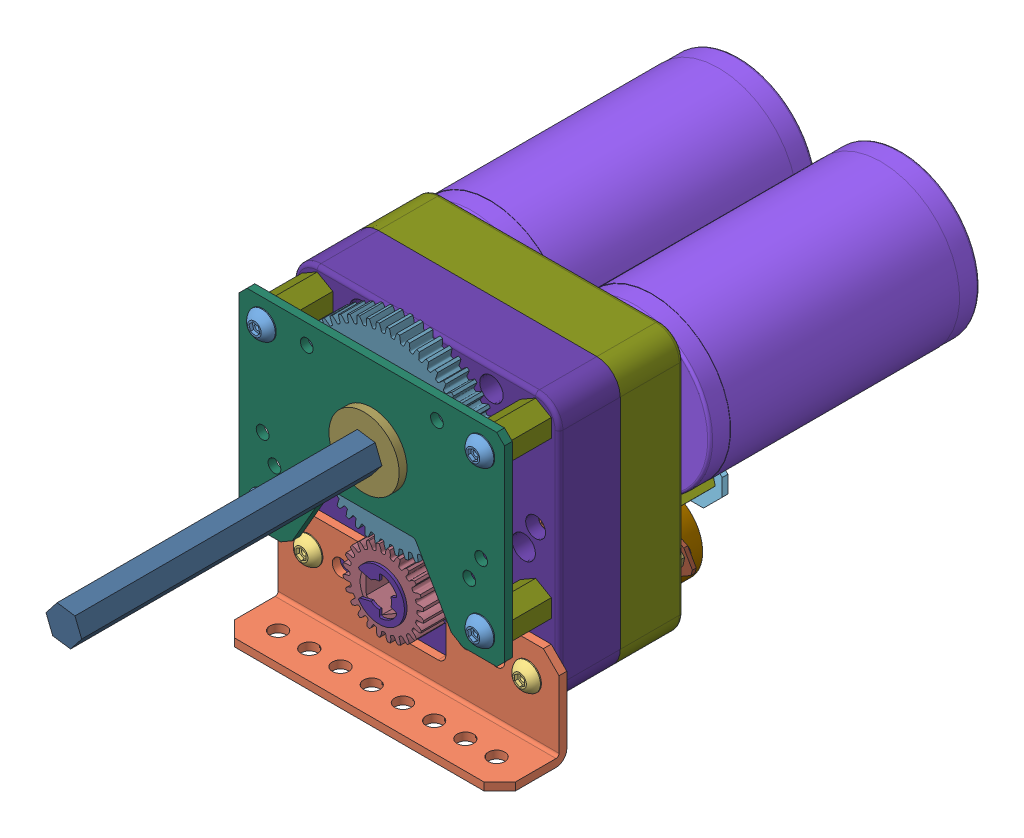
SolidWorks assembly 217-2615 wGrayhill Encoder.20130116_1, configuration Default. Lengths in mm.
Overall size (144.51 151.11 312.65).
83 component instances, 45 part files, 0 mates.
Components (placement in the parent):
- 217-2733-1: 217-2733 [Default] at (0 53.4162 12.0523) x (0 0 1) z (0.878299 0.478111 0) size (7.11 24.61 24.61)
- 217-2733-2: 217-2733 [Default] at (0 53.4162 -17.6911) x (0 0 -1) z (0.971421 0.237365 0) size (7.11 24.61 24.61)
- 217-2731-1: 217-2731 [Default] at (0 0 -25.6286) x (1 0 0) z (0 -1 0) size (31.12 7.94 31.12)
- 217-2789-1: 217-2789 [Default] at (0 0 17.6784) x (0 0 -1) z (0.997427 0.071687 0) size (11.1 38.4 38.4)
- 217-2788_57155K375-1: 217-2788_57155K375 [Default] at (0 0 -46.8376) x (0.615894 0.787829 0) z (0 0 1) size (9.53 9.53 3.17)
- 217-2428-012 Rev2-1: 217-2428-012 Rev2 [Default] at (0 0 -66.0019) size (63.5 22.23 2.29)
- 217-2428-027 Rev1_97414A630-1: 217-2428-027 Rev1_97414A630 [Default] at (0 0 -48.7426) x (0 0 -1) z (-0.538463 -0.842649 0) size (0.64 5.89 7.9)
- 217-2428-005 Rev1-1: 217-2428-005 Rev1 [Default] at (25.4 0 -44.6659) x (-0.968533 0.248884 0) z (0.248884 0.968533 0) size (7.33 38.98 6.35)
- 217-2428-005 Rev1-2: 217-2428-005 Rev1 [Default] at (-25.4 0 -44.6659) x (0.661665 -0.7498 0) z (-0.7498 -0.661665 0) size (7.33 38.98 6.35)
- SCREW-832-0375-1: SCREW-832-0375 [Default] at (25.4 0 -68.2117) x (0 0 1) z (-0.875404 0.483392 0) size (11.73 7.92 7.92)
- SCREW-832-0375-2: SCREW-832-0375 [Default] at (-25.4 0 -68.2117) x (0 0 1) z (-0.875404 0.483392 0) size (11.73 7.92 7.92)
- SCREW-832-0375-3: SCREW-832-0375 [Default] at (25.4 0 -20.2311) x (0 0 -1) z (1 0 0) size (11.73 7.92 7.92)
- SCREW-832-0375-4: SCREW-832-0375 [Default] at (-25.4 0 -20.2311) x (0 0 -1) z (0.999351 0.036025 0) size (11.73 7.92 7.92)
- 217-2428-016 Rev2_Spur01-1: 217-2428-016 Rev2_Spur01 [Default] at (0 0 -29.2676) x (0.982225 0.187706 0) z (0 0 1) size (40.67 40.74 13.3)
- 217-2428-017 Rev2-1: 217-2428-017 Rev2 [Default] at (12.7 -21.997 -29.2989) x (0.227501 -0.973778 0) z (0 0 1) size (14.73 14.73 7.37)
- 217-2428-019 Rev1-1: 217-2428-019 Rev1 [Default] at (12.7 -21.997 -46.2407) x (0.866025 0.5 0) z (0 0 1) size (50.8 19.05 1.57)
- 217-2428-006 Rev1-1: 217-2428-006 Rev1 [Default] at (32.079 -14.2875 -35.1409) x (-0.95139 -0.30799 0) z (-0.30799 0.95139 0) size (7.33 19.93 6.35)
- 217-2428-006 Rev1-2: 217-2428-006 Rev1 [Default] at (-3.6662 -34.925 -35.1409) x (-0.054239 0.998528 0) z (0.998528 0.054239 0) size (7.33 19.93 6.35)
- SCREW-832-0375-5: SCREW-832-0375 [Default] at (32.079 -14.2875 -20.2311) x (0 0 -1) z (0.980613 0.195955 0) size (11.73 7.92 7.92)
- SCREW-832-0375-6: SCREW-832-0375 [Default] at (-3.6662 -34.925 -20.2311) x (0 0 -1) z (-0.826375 -0.56312 0) size (11.73 7.92 7.92)
- SCREW-832-0375-7: SCREW-832-0375 [Default] at (-3.6662 -34.925 -48.4505) x (0 0 1) z (0.948865 0.315681 0) size (11.73 7.92 7.92)
- SCREW-832-0375-8: SCREW-832-0375 [Default] at (32.079 -14.2875 -48.4505) x (0 0 1) z (-0.875404 0.483392 0) size (11.73 7.92 7.92)
- SBS1_SBS1032-0500ZC-1: SBS1_SBS1032-0500ZC [Default] at (-39.6321 27.2942 -19.8755) x (0 0 -1) z (0.878202 0.478289 0) size (15.78 9.29 9.24)
- SBS1_SBS1032-0500ZC-2: SBS1_SBS1032-0500ZC [Default] at (-26.4841 76.3632 -19.8755) x (0 0 -1) z (0.751237 -0.660033 0) size (15.78 9.29 9.24)
- 217-2614-001_12t-1: 217-2614-001_12t [Default] at (-33.0581 51.8287 -4.1095) x (-0.965926 0.258819 0) z (0 0 1) size (18.29 18.29 19)
- 217-2761-001 rev1-1: 217-2761-001 rev1 [Default] at (-34.0416 48.1582 -9.5159) x (0.965926 -0.258819 0) z (0 0 1) size (2 2 20)
- SBS1_SBS1032-0500ZC-3: SBS1_SBS1032-0500ZC [Default] at (39.6321 27.2942 -19.8755) x (0 0 -1) z (0.618676 -0.785646 0) size (15.78 9.29 9.24)
- SBS1_SBS1032-0500ZC-4: SBS1_SBS1032-0500ZC [Default] at (26.4841 76.3632 -19.8755) x (0 0 -1) z (0.996655 0.081722 0) size (15.78 9.29 9.24)
- 217-2761-001 rev1-2: 217-2761-001 rev1 [Default] at (32.0746 55.4992 -9.5159) x (0.965926 0.258819 0) z (0 0 1) size (2 2 20)
- 217-2614-001_12t-2: 217-2614-001_12t [Default] at (33.0581 51.8287 -4.1095) x (0.965926 0.258819 0) z (0 0 1) size (18.29 18.29 19)
- 217-2428-001 Rev1-1: 217-2428-001 Rev1 [Default] at (0 53.4162 -25.6159) size (107.95 127.51 28.8)
- 217-2428-002 Rev2-1: 217-2428-002 Rev2 [Default] at (0 53.4162 24.9301) x (-1 0 0) z (0 0 -1) size (107.95 127.51 28.11)
- 217-2703-001-1: 217-2703-001 [Default] at (0 53.4162 4.5339) x (-0.958428 0.285334 0) z (0 0 1) size (33.29 33.29 12.65)
- 217-2707-001_40t-1: 217-2707-001_40t [Default] at (0 53.4162 -8.1661) x (0.726321 0.687356 0) z (0 0 1) size (53.62 53.62 12.65)
- SBS1_SBS0832-1750SS-1: SBS1_SBS0832-1750SS [Default] at (-44.45 36.7075 21.4249) x (0 0 -1) z (0.052618 -0.998615 0) size (47.11 8.01 7.99)
- SBS1_SBS0832-1750SS-2: SBS1_SBS0832-1750SS [Default] at (44.45 36.7075 21.4249) x (0 0 -1) z (0.699378 -0.714752 0) size (47.11 8.01 7.99)
- Nylock Nut_NNY2520-ZC-1: Nylock Nut_NNY2520-ZC [Default] at (44.45 -14.0925 -17.7546) x (0 1 0) z (0 0 -1) size (12.85 11.89 7.62)
- Nylock Nut_NNY2520-ZC-2: Nylock Nut_NNY2520-ZC [Default] at (44.45 74.8075 -17.7546) x (0 1 0) z (0 0 -1) size (12.85 11.89 7.62)
- 217-2428-004 Rev3-1: 217-2428-004 Rev3 [Default] at (0 53.4162 -2.8448) x (0.97269 0.232108 0) z (0 0 1) size (11 9.53 43.92)
- 217-2428-021 Rev1-1: 217-2428-021 Rev1 [Default] at (0 53.4162 -16.1036) x (0.999182 0.040427 0) z (0 0 1) size (15.88 15.88 3.17)
- 217-2428-029 Rev1-1: 217-2428-029 Rev1 [Default] at (0 53.4162 11.4173) size (15.88 15.88 1.12)
- Nylock 8-32-1: Nylock 8-32 [Default] at (44.45 36.7075 -19.2659) x (0.254216 0.967147 0) z (-0.967147 0.254216 0) size (10.2 4.9 8.12)
- Nylock 8-32-2: Nylock 8-32 [Default] at (-44.45 36.7075 -19.2659) x (0.948441 0.316954 0) z (-0.316954 0.948441 0) size (10.2 4.9 8.12)
- 217-2000-1: 217-2000 [Default] at (33.0581 51.8287 -25.6159) x (0 0 -1) z (0.965926 0.258819 0) size (150.2 64.01 64.01)
- 217-2000-2: 217-2000 [Default] at (-33.0581 51.8287 -25.6159) x (0 0 -1) z (-0.965926 0.258819 0) size (150.2 64.01 64.01)
- Grahill Encoder-1: Grahill Encoder [Default] at (12.7 -21.997 -41.7957) x (0.902286 -0.431138 0) z (0.431138 0.902286 0) size (31.75 31.12 31.75)
- 217-2617-003 Rev1-1: 217-2617-003 Rev1 [Default] at (0 53.4162 96.2376) x (-0.617144 -0.78685 0) z (0 0 1) size (14.66 12.7 152.4)
- 217-2743-1: 217-2743 [Default] at (0 53.4162 23.5648) x (0 0 -1) z (-0.999944 0.010604 0) size (7.94 28.58 28.58)
- 217-2734-1: 217-2734 [Default] at (0 53.4162 50.2793) x (0.990004 -0.141038 0) z (0.141038 0.990004 0) size (31.12 7.94 31.12)
- 217-2704-001_30-1: 217-2704-001_30 [Default] at (0 0 36.6903) x (-0.999979 -0.006492 0) z (0 0 1) size (33.29 33.29 12.65)
- 217-2714-001_60t-1: 217-2714-001_60t [Default] at (0 53.4162 36.0366) x (0.538346 -0.842724 0) z (0 0 1) size (78.95 78.95 12.65)
- 217-2617-001 Rev4-1: 217-2617-001 Rev4 [Default] at (0 30.3575 43.9293) size (107.95 82.55 3.18)
- 217-2617-002 Rev1_91780A359-1: 217-2617-002 Rev1_91780A359 [Default] at (-44.45 74.8075 31.2293) size (12.7 14.66 25.4)
- 217-2617-002 Rev1_91780A359-2: 217-2617-002 Rev1_91780A359 [Default] at (44.45 74.8075 31.2293) x (-0.5 -0.866025 0) z (0 0 1) size (12.7 14.66 25.4)
- 217-2617-002 Rev1_91780A359-3: 217-2617-002 Rev1_91780A359 [Default] at (-44.45 11.3075 31.2293) size (12.7 14.66 25.4)
- 217-2617-002 Rev1_91780A359-4: 217-2617-002 Rev1_91780A359 [Default] at (44.45 11.3075 31.2293) size (12.7 14.66 25.4)
- 217-2617-004 Rev1_97431A340_grv-1: 217-2617-004 Rev1_97431A340_grv [Default] at (0 0 43.5483) x (0 0 1) z (-1 0 0) size (1.07 20.42 18.58)
- 217-2617-004 Rev1_97431A340_grv-2: 217-2617-004 Rev1_97431A340_grv [Default] at (0 53.4162 29.1786) x (0 0 1) z (-1 0 0) size (1.07 20.42 18.58)
- SBS1_SBS2520-1750-1: SBS1_SBS2520-1750 [Default] at (44.45 11.3075 -18.1737) x (0 0 1) z (-0.961255 0.27566 0) size (48.48 11.22 11.17)
- SBS1_SBS2520-1750-2: SBS1_SBS2520-1750 [Default] at (44.45 74.8075 -18.1737) x (0 0 1) z (-0.983108 -0.183029 0) size (48.48 11.22 11.17)
- SBS1_SBS2520-1750-3: SBS1_SBS2520-1750 [Default] at (-44.45 74.8075 -18.1737) x (0 0 1) z (-0.878539 0.47767 0) size (48.48 11.22 11.17)
- SBS1_SBS2520-1750-4: SBS1_SBS2520-1750 [Default] at (-44.45 11.3075 -18.1737) x (0 0 1) z (-0.805318 -0.592843 0) size (48.48 11.22 11.17)
- SBS1_SBS2520-0625ZC-1: SBS1_SBS2520-0625ZC [Default] at (-44.45 74.8075 50.4571) x (0 0 -1) z (0.963378 0.268146 0) size (19.57 11.22 11.17)
- SBS1_SBS2520-0625ZC-2: SBS1_SBS2520-0625ZC [Default] at (-44.45 11.3075 50.4571) x (0 0 -1) z (-0.232142 -0.972682 0) size (19.57 11.22 11.17)
- SBS1_SBS2520-0625ZC-3: SBS1_SBS2520-0625ZC [Default] at (44.45 74.8075 50.4571) x (0 0 -1) z (-0.560912 -0.827875 0) size (19.57 11.22 11.17)
- SBS1_SBS2520-0625ZC-4: SBS1_SBS2520-0625ZC [Default] at (44.45 11.3075 50.4571) x (0 0 -1) z (0.367215 0.930136 0) size (19.57 11.22 11.17)
- 217-2428-024 Rev2-1: 217-2428-024 Rev2 [Default] at (0 -39.4925 40.1701) x (-1 0 0) z (0 1 0) size (114.3 27.31 38.1)
- Nylock Nut_NNY2520-ZC-3: Nylock Nut_NNY2520-ZC [Default] at (-44.45 -14.0925 -17.7546) x (0 1 0) z (0 0 -1) size (12.85 11.89 7.62)
- SBS1_SBS2520-2000ZC-1: SBS1_SBS2520-2000ZC [Default] at (-44.45 -14.0925 31.4579) x (0 0 -1) z (1 0 0) size (54.83 11.22 11.17)
- SBS1_SBS2520-2000ZC-2: SBS1_SBS2520-2000ZC [Default] at (44.45 -14.0925 31.4579) x (0 0 -1) z (1 0 0) size (54.83 11.22 11.17)
- 217-2428-032 Rev1-1: 217-2428-032 Rev1 [Default] at (0 0 -41.3766) x (-0.71017 -0.704031 0) z (0 0 -1) size (18.09 11.02 22.68)
- 217-2428-032 Rev1-2: 217-2428-032 Rev1 [Default] at (0 0 -41.3766) x (0.71017 0.704031 0) z (0 0 -1) size (18.09 11.02 22.68)
- 217-2778-NCQ8A075-050M_1032_Nut_90545A111-1: 217-2778-NCQ8A075-050M_1032_Nut_90545A111 [Default] at (0 0 -43.7261) x (0.71017 0.704031 0) z (0 0 -1) size (9.53 11 3.39)
- 91251A107_91251A107-1: 91251A107_91251A107 [Default] at (-8.112 -1.0893 -38.2016) x (0.504341 0.499981 0.704031) z (-0.704031 0.71017 0) size (4.65 4.65 10.79)
- 91251A107_91251A107-2: 91251A107_91251A107 [Default] at (8.112 1.0893 -38.2016) x (0.676772 0.670922 -0.303056) z (0.704031 -0.71017 0) size (4.65 4.65 10.79)
- 217-2428-023 Rev1_9714K3-1: 217-2428-023 Rev1_9714K3 [Default] at (0 0 10.8839) x (0.439772 0.898109 0) z (0.898109 -0.439772 0) size (26.82 4.09 25.81)
- 217-2428-027 Rev1_97414A630-2: 217-2428-027 Rev1_97414A630 [Default] at (0 0 -44.9326) x (0 0 -1) z (0.823209 -0.567739 0) size (0.64 5.89 7.9)
- SCREW-632-0250-1: SCREW-632-0250 [Default] at (-15.494 0 -61.8617) x (0 0 -1) z (1 0 0) size (8.2 6.59 6.59)
- SCREW-632-0250-2: SCREW-632-0250 [Default] at (15.494 0 -61.8617) x (0 0 -1) z (1 0 0) size (8.2 6.59 6.59)
- WFT323-0472-048SS-1: WFT323-0472-048SS [Default] at (44.45 74.8075 17.9197) x (-0.784478 -0.620156 0) z (-0.620156 0.784478 0) size (11.99 1.22 11.99)
- WFT323-0472-048SS-2: WFT323-0472-048SS [Default] at (44.45 11.3075 17.9197) x (-0.784478 -0.620156 0) z (-0.620156 0.784478 0) size (11.99 1.22 11.99)
- WFT323-0472-048SS-3: WFT323-0472-048SS [Default] at (-44.45 11.3075 17.9197) x (-0.784478 -0.620156 0) z (-0.620156 0.784478 0) size (11.99 1.22 11.99)
- WFT323-0472-048SS-4: WFT323-0472-048SS [Default] at (-44.45 74.8075 17.9197) x (-0.784478 -0.620156 0) z (-0.620156 0.784478 0) size (11.99 1.22 11.99)
